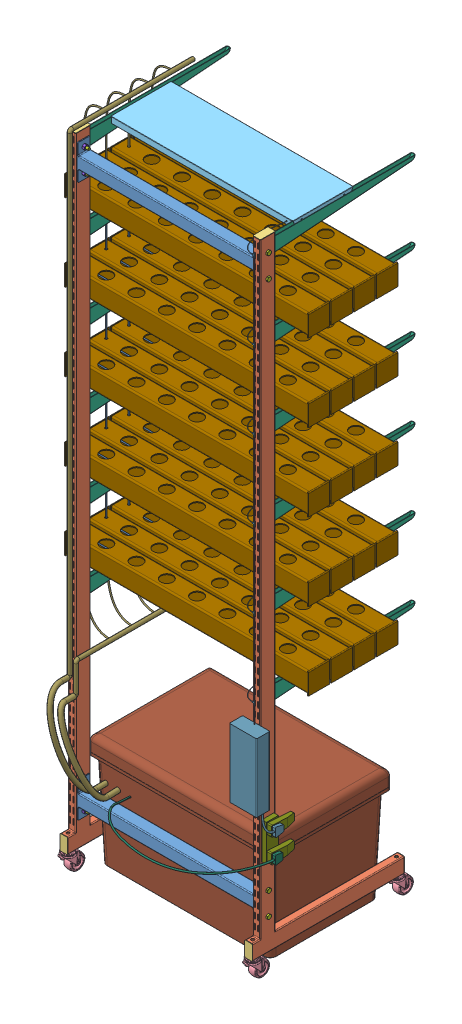
SolidWorks assembly plumbing, configuration Default. Lengths in mm.
Overall size (806 2127.7 608.88).
91 component instances, 17 part files, 242 mates.
Components (placement in the parent):
- TB-600-1: TB-600 [Default] at (0 2029.5 0) size (585 115 40)
- TB-600-2: TB-600 [Default] at (0 205.5 0) size (585 115 40)
- TSU-F-L-P-1: TSU-F-L-P [Default] at (305 113.5 -25) size (25 2050 500)
- TSU-F-L-P-2: TSU-F-L-P [Default] at (-305 113.5 -25) size (25 2050 500)
- TSU-CAP-1: TSU-CAP [Default] at (-305.1 113.6 -39.9) x (-1 0 0) z (0 0 -1) size (25.2 50.2 6.5)
- TSU-CAP-2: TSU-CAP [Default] at (304.9 113.6 -39.9) x (-1 0 0) z (0 0 -1) size (25.2 50.2 6.5)
- TSU-CAP-3: TSU-CAP [Default] at (305.1 1703.4 -25.1) x (1 0 0) z (0 1 0) size (25.2 50.2 6.5)
- TSU-CAP-4: TSU-CAP [Default] at (304.9 113.6 -360.1) size (25.2 50.2 6.5)
- TSU-CAP-5: TSU-CAP [Default] at (-304.9 1703.4 -25.1) x (1 0 0) z (0 1 0) size (25.2 50.2 6.5)
- TSU-CAP-6: TSU-CAP [Default] at (-304.9 113.6 -360.1) size (25.2 50.2 6.5)
- 2834T320_THREADED-STEM SWIVEL CASTER-1: 2834T320_THREADED-STEM SWIVEL CASTER [2834T32] at (305 82.55 -437.5) x (0 0 -1) z (1 0 0) size (67.73 101.87 56.07)
- 2834T320_THREADED-STEM SWIVEL CASTER-2: 2834T320_THREADED-STEM SWIVEL CASTER [2834T32] at (-305 82.55 37.5) x (0 0 -1) z (1 0 0) size (67.73 101.87 56.07)
- 2834T320_THREADED-STEM SWIVEL CASTER-3: 2834T320_THREADED-STEM SWIVEL CASTER [2834T32] at (305 82.55 37.5) x (0 0 -1) z (1 0 0) size (67.73 101.87 56.07)
- 2834T320_THREADED-STEM SWIVEL CASTER-4: 2834T320_THREADED-STEM SWIVEL CASTER [2834T32] at (-305 82.55 -437.5) x (0 0 -1) z (1 0 0) size (67.73 101.87 56.07)
- TSS-600-1: TSS-600 [Default] at (0 818 -198.7822) size (607 37.13 331.17)
- TSUB-1: TSUB [Default] at (305 766.5 -25) x (-1 0 0) z (0 0 -1) size (14.07 50.86 484.03)
- TSUB-2: TSUB [Default] at (-305 766.5 -25) x (-1 0 0) z (0 0 -1) size (14.07 50.86 484.03)
- TSUB-3: TSUB [Default] at (-305 1022.5 -25) x (-1 0 0) z (0 0 -1) size (14.07 50.86 484.03)
- TSUB-4: TSUB [Default] at (305 1022.5 -25) x (-1 0 0) z (0 0 -1) size (14.07 50.86 484.03)
- TSS-600-2: TSS-600 [Default] at (0 1074 -198.7822) size (607 37.13 331.17)
- TSUB-5: TSUB [Default] at (-305 1534.5 -25) x (-1 0 0) z (0 0 -1) size (14.07 50.86 484.03)
- TSUB-6: TSUB [Default] at (305 1534.5 -25) x (-1 0 0) z (0 0 -1) size (14.07 50.86 484.03)
- TSS-600-3: TSS-600 [Default] at (0 1586 -198.7822) size (607 37.13 331.17)
- TSUB-7: TSUB [Default] at (-305 2046.5 -25) x (-1 0 0) z (0 0 -1) size (14.07 50.86 484.03)
- TSUB-8: TSUB [Default] at (305 2046.5 -25) x (-1 0 0) z (0 0 -1) size (14.07 50.86 484.03)
- TSS-600-4: TSS-600 [Default] at (0 2098 -198.7822) size (607 37.13 331.17)
- TSUB-9: TSUB [Default] at (-305 1278.5 -25) x (-1 0 0) z (0 0 -1) size (14.07 50.86 484.03)
- TSUB-10: TSUB [Default] at (305 1278.5 -25) x (-1 0 0) z (0 0 -1) size (14.07 50.86 484.03)
- TSS-600-5: TSS-600 [Default] at (0 1330 -198.7822) size (607 37.13 331.17)
- TSUB-11: TSUB [Default] at (-305 1790.5 -25) x (-1 0 0) z (0 0 -1) size (14.07 50.86 484.03)
- TSUB-12: TSUB [Default] at (305 1790.5 -25) x (-1 0 0) z (0 0 -1) size (14.07 50.86 484.03)
- TSS-600-6: TSS-600 [Default] at (0 1842 -198.7822) size (607 37.13 331.17)
- hex bolt gradeab2_bsi-10: hex bolt gradeab2_bsi [BS EN 28765 - M8x1 x 45 x 22-N] at (322.8 2067 0) x (-1 0 0) z (0 -0.924225 -0.381849) size (50.3 15.01 13)
- hex bolt gradeab2_bsi-11: hex bolt gradeab2_bsi [BS EN 28765 - M8x1 x 45 x 22-N] at (322.8 1992 0) x (-1 0 0) z (0 -0.999974 0.007224) size (50.3 15.01 13)
- hex bolt gradeab2_bsi-12: hex bolt gradeab2_bsi [BS EN 28765 - M8x1 x 45 x 22-N] at (-322.8 2067 0) size (50.3 15.01 13)
- hex bolt gradeab2_bsi-13: hex bolt gradeab2_bsi [BS EN 28765 - M8x1 x 45 x 22-N] at (-322.8 1992 0) size (50.3 15.01 13)
- hex bolt gradeab2_bsi-14: hex bolt gradeab2_bsi [BS EN 28765 - M8x1 x 45 x 22-N] at (-322.8 168 0) size (50.3 15.01 13)
- hex bolt gradeab2_bsi-15: hex bolt gradeab2_bsi [BS EN 28765 - M8x1 x 45 x 22-N] at (-322.8 243 0) size (50.3 15.01 13)
- hex bolt gradeab2_bsi-16: hex bolt gradeab2_bsi [BS EN 28765 - M8x1 x 45 x 22-N] at (322.8 168 0) x (-1 0 0) z (0 0.924225 0.381849) size (50.3 15.01 13)
- hex bolt gradeab2_bsi-17: hex bolt gradeab2_bsi [BS EN 28765 - M8x1 x 45 x 22-N] at (322.8 243 0) x (-1 0 0) z (0 -0.924225 -0.381849) size (50.3 15.01 13)
- hex nut gradec_bsi-1: hex nut gradec_bsi [BS EN 24034 - M8 - N] at (281.6 2067 0) x (0 0 1) z (-1 0 0) size (13 15.01 7.9)
- hex nut gradec_bsi-2: hex nut gradec_bsi [BS EN 24034 - M8 - N] at (281.6 1992 0) x (0 0 1) z (-1 0 0) size (13 15.01 7.9)
- hex nut gradec_bsi-3: hex nut gradec_bsi [BS EN 24034 - M8 - N] at (-281.6 2067 0) x (0 0 -1) z (1 0 0) size (13 15.01 7.9)
- hex nut gradec_bsi-4: hex nut gradec_bsi [BS EN 24034 - M8 - N] at (-281.6 1992 0) x (0 0.383049 0.923728) z (1 0 0) size (13 15.01 7.9)
- hex nut gradec_bsi-5: hex nut gradec_bsi [BS EN 24034 - M8 - N] at (-281.6 243 0) x (0 0 -1) z (1 0 0) size (13 15.01 7.9)
- hex nut gradec_bsi-6: hex nut gradec_bsi [BS EN 24034 - M8 - N] at (281.6 243 0) x (0 0 1) z (-1 0 0) size (13 15.01 7.9)
- hex nut gradec_bsi-7: hex nut gradec_bsi [BS EN 24034 - M8 - N] at (281.6 168 0) x (0 0 1) z (-1 0 0) size (13 15.01 7.9)
- hex nut gradec_bsi-8: hex nut gradec_bsi [BS EN 24034 - M8 - N] at (-281.6 168 0) x (0 0 -1) z (1 0 0) size (13 15.01 7.9)
- GB-600-b-1: GB-600-b [Default] at (0 1106.5 -233.7344) size (806 70 70)
- GB-600-p-1: GB-600-p [Default] at (0 1106.5 -233.7344) size (92 218.31 4)
- GB-600-p-2: GB-600-p [Default] at (0 1106.5 -308.7344) size (92 218.31 4)
- GB-600-b-2: GB-600-b [Default] at (0 1106.5 -308.7344) size (806 70 70)
- GB-600-p-3: GB-600-p [Default] at (0 1106.5 -83.7344) size (92 218.31 4)
- GB-600-b-3: GB-600-b [Default] at (0 1106.5 -83.7344) size (806 70 70)
- GB-600-p-4: GB-600-p [Default] at (0 1106.5 -158.7344) size (92 218.31 4)
- GB-600-b-4: GB-600-b [Default] at (0 1106.5 -158.7344) size (806 70 70)
- GB-600-b-5: GB-600-b [Default] at (0 850.5 -83.7344) size (806 70 70)
- GB-600-b-6: GB-600-b [Default] at (0 850.5 -158.7344) size (806 70 70)
- GB-600-b-7: GB-600-b [Default] at (0 850.5 -233.7344) size (806 70 70)
- GB-600-b-8: GB-600-b [Default] at (0 850.5 -308.7344) size (806 70 70)
- GB-600-b-9: GB-600-b [Default] at (0 1618.5 -83.7344) size (806 70 70)
- GB-600-b-10: GB-600-b [Default] at (0 1618.5 -158.7344) size (806 70 70)
- GB-600-b-11: GB-600-b [Default] at (0 1618.5 -233.7344) size (806 70 70)
- GB-600-b-12: GB-600-b [Default] at (0 1618.5 -308.7344) size (806 70 70)
- GB-600-p-5: GB-600-p [Default] at (0 1618.5 -83.7344) size (92 218.31 4)
- GB-600-p-6: GB-600-p [Default] at (0 1618.5 -158.7344) size (92 218.31 4)
- GB-600-p-7: GB-600-p [Default] at (0 1618.5 -233.7344) size (92 218.31 4)
- GB-600-p-8: GB-600-p [Default] at (0 1618.5 -308.7344) size (92 218.31 4)
- GB-600-p-9: GB-600-p [Default] at (0 1362.5 -308.7344) size (92 218.31 4)
- GB-600-p-10: GB-600-p [Default] at (0 1362.5 -233.7344) size (92 218.31 4)
- GB-600-p-11: GB-600-p [Default] at (0 1362.5 -158.7344) size (92 218.31 4)
- GB-600-p-12: GB-600-p [Default] at (0 1362.5 -83.7344) size (92 218.31 4)
- GB-600-b-13: GB-600-b [Default] at (0 1362.5 -308.7344) size (806 70 70)
- GB-600-b-14: GB-600-b [Default] at (0 1362.5 -233.7344) size (806 70 70)
- GB-600-b-15: GB-600-b [Default] at (0 1362.5 -158.7344) size (806 70 70)
- GB-600-b-16: GB-600-b [Default] at (0 1362.5 -83.7344) size (806 70 70)
- GB-600-p-13: GB-600-p [Default] at (0 1874.5 -308.7344) size (92 218.31 4)
- GB-600-p-14: GB-600-p [Default] at (0 1874.5 -233.7344) size (92 218.31 4)
- GB-600-p-15: GB-600-p [Default] at (0 1874.5 -158.7344) size (92 218.31 4)
- GB-600-p-16: GB-600-p [Default] at (0 1874.5 -83.7344) size (92 218.31 4)
- GB-600-b-17: GB-600-b [Default] at (0 1874.5 -83.7344) size (806 70 70)
- GB-600-b-18: GB-600-b [Default] at (0 1874.5 -158.7344) size (806 70 70)
- GB-600-b-19: GB-600-b [Default] at (0 1874.5 -233.7344) size (806 70 70)
- GB-600-b-20: GB-600-b [Default] at (0 1874.5 -308.7344) size (806 70 70)
- Part3-1: Part3 [Default] at (0 320 -225) size (600 370 400)
- Part4-1: Part4 [Default] at origin
- Part5-1: Part5 [Default] at (-305 113.5 25) size (241.4 2067.5 489.85)
- Part1-1: Part1 [Default] at (0 2060.8692 -198.7822) x (-1 0 0) z (0 -1 0) size (2 2 1357)
- Part2-1: Part2 [Default] at (305 113.5 -25) x (0 0 -1) z (1 0 0) size (82.56 307.09 97.63)
- ele-1: ele [Default] at (0 5 -225) x (1 0 0) z (0 1 0) size (624.24 196.22 364.08)
- power brick-1: power brick [Default] at (317.5 113.5 -25) x (0 0 -1) z (1 0 0) size (82.62 120 30)
Mates (geometry in assembly coordinates):
- Coincident5: coincident aligned: plane of TB-600-2 through (0 205.5 0) normal (1 0 0)
- Coincident6: coincident aligned: plane of TB-600-2 through (0 205.5 0) normal (0 0 1)
- Tangent1: tangent anti-aligned: torus of 2834T320_THREADED-STEM SWIVEL CASTER-1
- Concentric5: concentric anti-aligned: cylinder of TSU-F-L-P-1 through (305 113.5 -437.5) axis (0 -1 0) radius 5.1; cylinder of 2834T320_THREADED-STEM SWIVEL CASTER-1 through (305 101.6 -437.5) axis (0 1 0) radius 4.7625
- Coincident7: coincident anti-aligned: plane of TB-600-2 through (292.5 205.5 0) normal (1 0 0); plane of TSU-F-L-P-1 through (292.5 2113.5 -22) normal (-1 0 0)
- Concentric6: concentric anti-aligned: cylinder of TB-600-2 through (292.5 243 0) axis (-1 0 0) radius 4.5; cylinder of TSU-F-L-P-1 through (290.9 243 0) axis (1 0 0) radius 4.5
- Coincident8: coincident anti-aligned: plane of TSU-F-L-P-1 through (305 63.5 -450) normal (0 -1 0); plane of 2834T320_THREADED-STEM SWIVEL CASTER-1 through (305 63.5 -421.3957) normal (0 1 0)
- Concentric7: concentric anti-aligned: cylinder of TB-600-1 through (292.5 2067 0) axis (-1 0 0) radius 4.5; cylinder of TSU-F-L-P-1 through (292.5 2067 0) axis (1 0 0) radius 4.5
- Coincident9: coincident anti-aligned: plane of TB-600-1 through (292.5 2029.5 0) normal (1 0 0); plane of TSU-F-L-P-1 through (292.5 2113.5 -22) normal (-1 0 0)
- Concentric8: concentric aligned: cylinder of TB-600-2 through (-292.5 168 0) axis (1 0 0) radius 4.5; cylinder of TSU-F-L-P-2 through (-319.1 168 0) axis (1 0 0) radius 4.5
- Coincident10: coincident anti-aligned: plane of TB-600-2 through (-292.5 205.5 0) normal (-1 0 0); plane of TSU-F-L-P-2 through (-292.5 2113.5 -22) normal (1 0 0)
- Concentric9: concentric anti-aligned: cylinder of TSU-F-L-P-2 through (-305 113.5 -437.5) axis (0 -1 0) radius 5.1; cylinder of 2834T320_THREADED-STEM SWIVEL CASTER-4 through (-305 101.6 -437.5) axis (0 1 0) radius 4.7625
- Concentric10: concentric aligned: cylinder of TB-600-1 through (-292.5 1992 0) axis (1 0 0) radius 4.5; cylinder of TSU-F-L-P-2 through (-317.5 1992 0) axis (1 0 0) radius 4.5
- Concentric11: concentric aligned: cylinder of TB-600-1 through (-292.5 2067 0) axis (1 0 0) radius 4.5; cylinder of TSU-F-L-P-2 through (-317.5 2067 0) axis (1 0 0) radius 4.5
- Parallel4: parallel aligned: plane of TSU-F-L-P-1 through (317.5 2113.5 -22) normal (1 0 0); plane of 2834T320_THREADED-STEM SWIVEL CASTER-1 through (316.9062 47.2916 -458.1375) normal (1 0 0)
- Coincident16: coincident anti-aligned: plane of TSU-F-L-P-2 through (-305 63.5 -450) normal (0 -1 0); plane of 2834T320_THREADED-STEM SWIVEL CASTER-4 through (-305 63.5 -421.3957) normal (0 1 0)
- Concentric12: concentric anti-aligned: cylinder of TSU-F-L-P-1 through (305 113.5 37.5) axis (0 -1 0) radius 5.1; cylinder of 2834T320_THREADED-STEM SWIVEL CASTER-3 through (305 101.6 37.5) axis (0 1 0) radius 4.7625
- Coincident17: coincident anti-aligned: plane of TSU-F-L-P-1 through (305 63.5 -450) normal (0 -1 0); plane of 2834T320_THREADED-STEM SWIVEL CASTER-3 through (305 63.5 53.6043) normal (0 1 0)
- Coincident18: coincident aligned: plane of 2834T320_THREADED-STEM SWIVEL CASTER-1 through (316.9062 47.2916 -458.1375) normal (1 0 0); plane of 2834T320_THREADED-STEM SWIVEL CASTER-3 through (316.9062 47.2916 16.8625) normal (1 0 0)
- Concentric13: concentric anti-aligned: cylinder of TSU-F-L-P-2 through (-305 113.5 37.5) axis (0 -1 0) radius 5.1; cylinder of 2834T320_THREADED-STEM SWIVEL CASTER-2 through (-305 101.6 37.5) axis (0 1 0) radius 4.7625
- Coincident19: coincident anti-aligned: plane of TSU-F-L-P-2 through (-305 63.5 -450) normal (0 -1 0); plane of 2834T320_THREADED-STEM SWIVEL CASTER-2 through (-305 63.5 53.6043) normal (0 1 0)
- Parallel6: parallel aligned: plane of TSU-F-L-P-2 through (-317.5 2113.5 -22) normal (-1 0 0); plane of 2834T320_THREADED-STEM SWIVEL CASTER-2 through (-316.9062 47.2916 16.8625) normal (-1 0 0)
- Coincident21: coincident anti-aligned: plane of TSU-F-L-P-1 through (294 2113.5 0) normal (1 0 0); plane of TSU-CAP-4 through (294 113.6 45) normal (-1 0 0)
- Coincident22: coincident anti-aligned: plane of TSU-F-L-P-1 through (314.5 112 -450) normal (0 -1 0); plane of TSU-CAP-4 through (304.9 112 45) normal (0 1 0)
- Coincident23: coincident anti-aligned: plane of TSU-F-L-P-1 through (314.5 110.5 50) normal (0 0 1); plane of TSU-CAP-4 through (304.9 113.6 50) normal (0 0 -1)
- Coincident24: coincident anti-aligned: plane of TSU-F-L-P-2 through (-294 2113.5 0) normal (-1 0 0); plane of TSU-CAP-6 through (-294 113.6 45) normal (1 0 0)
- Coincident25: coincident anti-aligned: plane of TSU-F-L-P-2 through (-295.5 112 -450) normal (0 -1 0); plane of TSU-CAP-6 through (-304.9 112 45) normal (0 1 0)
- Coincident26: coincident anti-aligned: plane of TSU-F-L-P-2 through (-295.5 110.5 50) normal (0 0 1); plane of TSU-CAP-6 through (-304.9 113.6 50) normal (0 0 -1)
- Coincident27: coincident anti-aligned: plane of TSU-F-L-P-1 through (294 2113.5 0) normal (1 0 0); plane of TSU-CAP-2 through (294 113.6 -445) normal (-1 0 0)
- Coincident28: coincident anti-aligned: plane of TSU-F-L-P-1 through (314.5 112 -450) normal (0 -1 0); plane of TSU-CAP-2 through (304.9 112 -445) normal (0 1 0)
- Coincident29: coincident anti-aligned: plane of TSU-F-L-P-1 through (314.5 110.5 -450) normal (0 0 -1); plane of TSU-CAP-2 through (304.9 113.6 -450) normal (0 0 1)
- Coincident30: coincident anti-aligned: plane of TSU-F-L-P-2 through (-316 2113.5 0) normal (1 0 0); plane of TSU-CAP-1 through (-316 113.6 -445) normal (-1 0 0)
- Coincident31: coincident anti-aligned: plane of TSU-F-L-P-2 through (-295.5 112 -450) normal (0 -1 0); plane of TSU-CAP-1 through (-305.1 112 -445) normal (0 1 0)
- Coincident32: coincident anti-aligned: plane of TSU-F-L-P-2 through (-295.5 110.5 -450) normal (0 0 -1); plane of TSU-CAP-1 through (-305.1 113.6 -450) normal (0 0 1)
- Coincident33: coincident anti-aligned: plane of TSU-F-L-P-1 through (316 2113.5 0) normal (-1 0 0); plane of TSU-CAP-3 through (316 2108.5 -25.1) normal (1 0 0)
- Coincident34: coincident anti-aligned: plane of TSU-F-L-P-1 through (314.5 2113.5 -23.5) normal (0 0 1); plane of TSU-CAP-3 through (305.1 2108.5 -23.5) normal (0 0 -1)
- Coincident35: coincident anti-aligned: plane of TSU-F-L-P-1 through (314.5 2113.5 -22) normal (0 1 0); plane of TSU-CAP-3 through (305.1 2113.5 -25.1) normal (0 -1 0)
- Coincident36: coincident anti-aligned: plane of TSU-F-L-P-2 through (-294 2113.5 0) normal (-1 0 0); plane of TSU-CAP-5 through (-294 2108.5 -25.1) normal (1 0 0)
- Coincident37: coincident anti-aligned: plane of TSU-F-L-P-2 through (-295.5 2113.5 -23.5) normal (0 0 1); plane of TSU-CAP-5 through (-304.9 2108.5 -23.5) normal (0 0 -1)
- Coincident38: coincident anti-aligned: plane of TSU-F-L-P-2 through (-295.5 2113.5 -22) normal (0 1 0); plane of TSU-CAP-5 through (-304.9 2113.5 -25.1) normal (0 -1 0)
- Parallel7: parallel aligned: plane of TSU-F-L-P-2 through (-292.5 2113.5 -22) normal (1 0 0); plane of 2834T320_THREADED-STEM SWIVEL CASTER-4 through (-293.0938 47.2916 -458.1375) normal (1 0 0)
- Coincident41: coincident anti-aligned: plane of TSU-F-L-P-1 through (298 273.5 0.001) normal (1 0 0); plane of TSUB-1 through (298 766.5 -25) normal (-1 0 0)
- Coincident42: coincident anti-aligned: plane of TSU-F-L-P-1 through (305 2113.5 -25) normal (0 0 -1); plane of TSUB-1 through (312 766.5 -25) normal (0 0 1)
- Parallel8: parallel: line of TSU-F-L-P-1 through (309 342 -23.5) axis (0 0 -1); plane of TSUB-1 through (298 816.5 -25) normal (0 1 0)
- Coincident44: coincident anti-aligned: plane of TSS-600-1 through (299.5 798 -198.7822) normal (-1 0 0); plane of TSUB-1 through (299.5 766.5 -25) normal (1 0 0)
- Coincident45: coincident anti-aligned: plane of TSS-600-1 through (301 816.5 -100.2822) normal (0 -1 0); plane of TSUB-1 through (298 816.5 -25) normal (0 1 0)
- Coincident46: coincident anti-aligned: plane of TSU-F-L-P-2 through (-312 369.5 0.001) normal (1 0 0); plane of TSUB-2 through (-312 766.5 -25) normal (-1 0 0)
- Coincident47: coincident anti-aligned: plane of TSU-F-L-P-2 through (-305 2113.5 -25) normal (0 0 -1); plane of TSUB-2 through (-312 766.5 -25) normal (0 0 1)
- Coincident48: coincident anti-aligned: plane of TSS-600-1 through (301 816.5 -100.2822) normal (0 -1 0); plane of TSUB-2 through (-312 816.5 -25) normal (0 1 0)
- Coincident49: coincident anti-aligned: plane of TSU-F-L-P-1 through (312 1041.5 0.001) normal (-1 0 0); plane of TSUB-4 through (312 1022.5 -25) normal (1 0 0)
- Coincident50: coincident anti-aligned: plane of TSU-F-L-P-1 through (305 2113.5 -25) normal (0 0 -1); plane of TSUB-4 through (312 1022.5 -25) normal (0 0 1)
- Coincident51: coincident anti-aligned: plane of TSU-F-L-P-2 through (-298 1073.5 0.001) normal (-1 0 0); plane of TSUB-3 through (-298 1022.5 -25) normal (1 0 0)
- Coincident52: coincident anti-aligned: plane of TSU-F-L-P-2 through (-305 2113.5 -25) normal (0 0 -1); plane of TSUB-3 through (-312 1022.5 -25) normal (0 0 1)
- Coincident53: coincident anti-aligned: plane of TSUB-4 through (298 1072.5 -25) normal (0 1 0); plane of TSS-600-2 through (301 1072.5 -100.2822) normal (0 -1 0)
- Coincident54: coincident anti-aligned: plane of TSUB-3 through (-312 1072.5 -25) normal (0 1 0); plane of TSS-600-2 through (301 1072.5 -100.2822) normal (0 -1 0)
- Coincident55: coincident anti-aligned: plane of TSUB-4 through (299.5 1022.5 -25) normal (1 0 0); plane of TSS-600-2 through (299.5 1054 -198.7822) normal (-1 0 0)
- Coincident56: coincident anti-aligned: plane of TSUB-6 through (299.5 1534.5 -25) normal (1 0 0); plane of TSS-600-3 through (299.5 1566 -198.7822) normal (-1 0 0)
- Coincident57: coincident anti-aligned: plane of TSUB-6 through (298 1584.5 -25) normal (0 1 0); plane of TSS-600-3 through (301 1584.5 -100.2822) normal (0 -1 0)
- Coincident58: coincident anti-aligned: plane of TSUB-5 through (-312 1584.5 -25) normal (0 1 0); plane of TSS-600-3 through (301 1584.5 -100.2822) normal (0 -1 0)
- Coincident59: coincident anti-aligned: plane of TSUB-8 through (299.5 2046.5 -25) normal (1 0 0); plane of TSS-600-4 through (299.5 2078 -198.7822) normal (-1 0 0)
- Coincident60: coincident anti-aligned: plane of TSUB-8 through (298 2096.5 -25) normal (0 1 0); plane of TSS-600-4 through (301 2096.5 -100.2822) normal (0 -1 0)
- Coincident61: coincident anti-aligned: plane of TSUB-7 through (-312 2096.5 -25) normal (0 1 0); plane of TSS-600-4 through (301 2096.5 -100.2822) normal (0 -1 0)
- Coincident62: coincident anti-aligned: plane of TSUB-10 through (299.5 1278.5 -25) normal (1 0 0); plane of TSS-600-5 through (299.5 1310 -198.7822) normal (-1 0 0)
- Coincident63: coincident anti-aligned: plane of TSUB-10 through (298 1328.5 -25) normal (0 1 0); plane of TSS-600-5 through (301 1328.5 -100.2822) normal (0 -1 0)
- Coincident64: coincident anti-aligned: plane of TSUB-9 through (-312 1328.5 -25) normal (0 1 0); plane of TSS-600-5 through (301 1328.5 -100.2822) normal (0 -1 0)
- Coincident65: coincident anti-aligned: plane of TSUB-12 through (299.5 1790.5 -25) normal (1 0 0); plane of TSS-600-6 through (299.5 1822 -198.7822) normal (-1 0 0)
- Coincident66: coincident anti-aligned: plane of TSUB-12 through (298 1840.5 -25) normal (0 1 0); plane of TSS-600-6 through (301 1840.5 -100.2822) normal (0 -1 0)
- Coincident67: coincident anti-aligned: plane of TSUB-11 through (-312 1840.5 -25) normal (0 1 0); plane of TSS-600-6 through (301 1840.5 -100.2822) normal (0 -1 0)
- Coincident70: coincident anti-aligned: plane of TSU-F-L-P-1 through (305 2113.5 -25) normal (0 0 -1); plane of TSUB-10 through (298 1278.5 -25) normal (0 0 1)
- Coincident71: coincident anti-aligned: plane of TSU-F-L-P-2 through (-305 2113.5 -25) normal (0 0 -1); plane of TSUB-9 through (-312 1278.5 -25) normal (0 0 1)
- Coincident72: coincident aligned: plane of TSUB-3 through (-298 1022.5 -25) normal (1 0 0); plane of TSUB-9 through (-298 1278.5 -25) normal (1 0 0)
- Coincident73: coincident aligned: plane of TSUB-4 through (298 1022.5 -25) normal (-1 0 0); plane of TSUB-10 through (298 1278.5 -25) normal (-1 0 0)
- Coincident74: coincident anti-aligned: plane of TSU-F-L-P-1 through (305 2113.5 -25) normal (0 0 -1); plane of TSUB-6 through (298 1534.5 -25) normal (0 0 1)
- Coincident75: coincident anti-aligned: plane of TSU-F-L-P-2 through (-305 2113.5 -25) normal (0 0 -1); plane of TSUB-5 through (-312 1534.5 -25) normal (0 0 1)
- Coincident76: coincident aligned: plane of TSUB-5 through (-298 1534.5 -25) normal (1 0 0); plane of TSUB-9 through (-298 1278.5 -25) normal (1 0 0)
- Coincident78: coincident aligned: plane of TSUB-6 through (312 1534.5 -25) normal (1 0 0); plane of TSUB-12 through (312 1790.5 -25) normal (1 0 0)
- Coincident79: coincident aligned: plane of TSUB-6 through (298 1534.5 -25) normal (-1 0 0); plane of TSUB-10 through (298 1278.5 -25) normal (-1 0 0)
- Coincident80: coincident anti-aligned: plane of TSU-F-L-P-1 through (305 2113.5 -25) normal (0 0 -1); plane of TSUB-12 through (298 1790.5 -25) normal (0 0 1)
- Coincident81: coincident anti-aligned: plane of TSU-F-L-P-2 through (-312 1873.5 0.001) normal (1 0 0); plane of TSUB-11 through (-312 1790.5 -25) normal (-1 0 0)
- Coincident82: coincident anti-aligned: plane of TSU-F-L-P-2 through (-305 2113.5 -25) normal (0 0 -1); plane of TSUB-11 through (-312 1790.5 -25) normal (0 0 1)
- Coincident83: coincident anti-aligned: plane of TSU-F-L-P-2 through (-312 1969.5 0.001) normal (1 0 0); plane of TSUB-7 through (-312 2046.5 -25) normal (-1 0 0)
- Coincident84: coincident anti-aligned: plane of TSU-F-L-P-2 through (-305 2113.5 -25) normal (0 0 -1); plane of TSUB-7 through (-312 2046.5 -25) normal (0 0 1)
- Coincident85: coincident anti-aligned: plane of TSU-F-L-P-1 through (298 2001.5 0.001) normal (1 0 0); plane of TSUB-8 through (298 2046.5 -25) normal (-1 0 0)
- Coincident86: coincident anti-aligned: plane of TSU-F-L-P-1 through (305 2113.5 -25) normal (0 0 -1); plane of TSUB-8 through (298 2046.5 -25) normal (0 0 1)
- Coincident89: coincident: line of TSU-F-L-P-1 through (309 2070 -23.5) axis (0 0 -1); plane of TSUB-8 through (333.2603 2070 -25) normal (0 1 0)
- Coincident90: coincident aligned: plane of TSS-600-4 through (301 2098 -298.7822) normal (0 0 -1); plane of TSS-600-6 through (301 1842 -298.7822) normal (0 0 -1)
- Coincident91: coincident aligned: plane of TSS-600-3 through (301 1586 -298.7822) normal (0 0 -1); plane of TSS-600-6 through (301 1842 -298.7822) normal (0 0 -1)
- Coincident93: coincident aligned: plane of TSS-600-3 through (301 1586 -298.7822) normal (0 0 -1); plane of TSS-600-5 through (301 1330 -298.7822) normal (0 0 -1)
- Coincident94: coincident aligned: plane of TSS-600-2 through (301 1074 -298.7822) normal (0 0 -1); plane of TSS-600-5 through (301 1330 -298.7822) normal (0 0 -1)
- Coincident95: coincident aligned: plane of TSS-600-1 through (301 818 -298.7822) normal (0 0 -1); plane of TSS-600-2 through (301 1074 -298.7822) normal (0 0 -1)
- Coincident153: coincident: line of TSU-F-L-P-1 through (312 1814 -23.5) axis (0 0 -1); plane of TSUB-12 through (333.2603 1814 -25) normal (0 1 0)
- Coincident155: coincident: line of TSU-F-L-P-1 through (312 1558 -23.5) axis (0 0 -1); plane of TSUB-6 through (333.2603 1558 -25) normal (0 1 0)
- Coincident157: coincident: line of TSU-F-L-P-1 through (312 1302 -23.5) axis (0 0 -1); plane of TSUB-10 through (333.2603 1302 -25) normal (0 1 0)
- Coincident159: coincident: line of TSU-F-L-P-1 through (312 1046 -23.5) axis (0 0 -1); plane of TSUB-4 through (333.2603 1046 -25) normal (0 1 0)
- Coincident167: coincident: line of TSU-F-L-P-1 through (312 790 -23.5) axis (0 0 -1); plane of TSUB-1 through (333.2603 790 -25) normal (0 1 0)
- Concentric15: concentric aligned: cylinder of TSU-F-L-P-1 through (292.5 2067 0) axis (1 0 0) radius 4.5; cylinder of hex bolt gradeab2_bsi-10 through (322.8 2067 0) axis (1 0 0) radius 4
- Coincident181: coincident anti-aligned: plane of TSU-F-L-P-1 through (317.5 2113.5 -22) normal (1 0 0); plane of hex bolt gradeab2_bsi-10 through (317.5 2069.866 -6.9368) normal (-1 0 0)
- Concentric16: concentric aligned: cylinder of TSU-F-L-P-1 through (292.5 1992 0) axis (1 0 0) radius 4.5; cylinder of hex bolt gradeab2_bsi-11 through (322.8 1992 0) axis (1 0 0) radius 4
- Coincident182: coincident anti-aligned: plane of TSU-F-L-P-1 through (317.5 2113.5 -22) normal (1 0 0); plane of hex bolt gradeab2_bsi-11 through (317.5 1991.9458 -7.5054) normal (-1 0 0)
- Concentric17: concentric anti-aligned: cylinder of TB-600-1 through (-292.5 2067 0) axis (1 0 0) radius 4.5; cylinder of hex bolt gradeab2_bsi-12 through (-322.8 2067 0) axis (-1 0 0) radius 4
- Coincident183: coincident anti-aligned: plane of TSU-F-L-P-2 through (-317.5 2113.5 -22) normal (-1 0 0); plane of hex bolt gradeab2_bsi-12 through (-317.5 2074.5056 0) normal (1 0 0)
- Concentric18: concentric anti-aligned: cylinder of TB-600-1 through (-292.5 1992 0) axis (1 0 0) radius 4.5; cylinder of hex bolt gradeab2_bsi-13 through (-322.8 1992 0) axis (-1 0 0) radius 4
- Coincident184: coincident anti-aligned: plane of TSU-F-L-P-2 through (-317.5 2113.5 -22) normal (-1 0 0); plane of hex bolt gradeab2_bsi-13 through (-317.5 1999.5056 0) normal (1 0 0)
- Concentric19: concentric anti-aligned: cylinder of TB-600-2 through (-292.5 243 0) axis (1 0 0) radius 4.5; cylinder of hex bolt gradeab2_bsi-15 through (-322.8 243 0) axis (-1 0 0) radius 4
- Coincident185: coincident anti-aligned: plane of TSU-F-L-P-2 through (-317.5 2113.5 -22) normal (-1 0 0); plane of hex bolt gradeab2_bsi-15 through (-317.5 250.5056 0) normal (1 0 0)
- Concentric20: concentric anti-aligned: cylinder of TB-600-2 through (-292.5 168 0) axis (1 0 0) radius 4.5; cylinder of hex bolt gradeab2_bsi-14 through (-322.8 168 0) axis (-1 0 0) radius 4
- Coincident186: coincident anti-aligned: plane of TSU-F-L-P-2 through (-317.5 2113.5 -22) normal (-1 0 0); plane of hex bolt gradeab2_bsi-14 through (-317.5 175.5056 0) normal (1 0 0)
- Concentric21: concentric anti-aligned: cylinder of TB-600-2 through (292.5 243 0) axis (-1 0 0) radius 4.5; cylinder of hex bolt gradeab2_bsi-17 through (322.8 243 0) axis (1 0 0) radius 4
- Coincident187: coincident anti-aligned: plane of TSU-F-L-P-1 through (317.5 2113.5 -22) normal (1 0 0); plane of hex bolt gradeab2_bsi-17 through (317.5 245.866 -6.9368) normal (-1 0 0)
- Concentric22: concentric aligned: cylinder of TSU-F-L-P-1 through (290.9 168 0) axis (1 0 0) radius 4.5; cylinder of hex bolt gradeab2_bsi-16 through (322.8 168 0) axis (1 0 0) radius 4
- Coincident188: coincident anti-aligned: plane of TSU-F-L-P-1 through (317.5 2113.5 -22) normal (1 0 0); plane of hex bolt gradeab2_bsi-16 through (317.5 165.134 6.9368) normal (-1 0 0)
- Concentric23: concentric anti-aligned: cylinder of hex bolt gradeab2_bsi-10 through (322.8 2067 0) axis (1 0 0) radius 4; cylinder of hex nut gradec_bsi-1 through (289.5 2067 0) axis (-1 0 0) radius 3.4
- Coincident189: coincident anti-aligned: plane of TB-600-1 through (289.5 2029.5 0) normal (-1 0 0); plane of hex nut gradec_bsi-1 through (289.5 2074.5056 0) normal (1 0 0)
- Concentric24: concentric anti-aligned: cylinder of hex bolt gradeab2_bsi-11 through (322.8 1992 0) axis (1 0 0) radius 4; cylinder of hex nut gradec_bsi-2 through (289.5 1992 0) axis (-1 0 0) radius 3.4
- Coincident190: coincident anti-aligned: plane of TB-600-1 through (289.5 2029.5 0) normal (-1 0 0); plane of hex nut gradec_bsi-2 through (289.5 1999.5056 0) normal (1 0 0)
- Concentric25: concentric anti-aligned: cylinder of hex bolt gradeab2_bsi-12 through (-322.8 2067 0) axis (-1 0 0) radius 4; cylinder of hex nut gradec_bsi-3 through (-289.5 2067 0) axis (1 0 0) radius 3.4
- Coincident191: coincident anti-aligned: plane of TB-600-1 through (-289.5 2029.5 0) normal (1 0 0); plane of hex nut gradec_bsi-3 through (-289.5 2074.5056 0) normal (-1 0 0)
- Concentric26: concentric anti-aligned: cylinder of hex bolt gradeab2_bsi-13 through (-322.8 1992 0) axis (-1 0 0) radius 4; cylinder of hex nut gradec_bsi-4 through (-289.5 1992 0) axis (1 0 0) radius 3.4
- Coincident192: coincident anti-aligned: plane of TB-600-1 through (-289.5 2029.5 0) normal (1 0 0); plane of hex nut gradec_bsi-4 through (-289.5 1985.0669 2.875) normal (-1 0 0)
- Concentric27: concentric anti-aligned: cylinder of hex bolt gradeab2_bsi-15 through (-322.8 243 0) axis (-1 0 0) radius 4; cylinder of hex nut gradec_bsi-5 through (-289.5 243 0) axis (1 0 0) radius 3.4
- Coincident193: coincident anti-aligned: plane of TB-600-2 through (-289.5 205.5 0) normal (1 0 0); plane of hex nut gradec_bsi-5 through (-289.5 250.5056 0) normal (-1 0 0)
- Concentric28: concentric anti-aligned: cylinder of hex bolt gradeab2_bsi-14 through (-322.8 168 0) axis (-1 0 0) radius 4; cylinder of hex nut gradec_bsi-8 through (-289.5 168 0) axis (1 0 0) radius 3.4
- Coincident194: coincident anti-aligned: plane of TB-600-2 through (-289.5 205.5 0) normal (1 0 0); plane of hex nut gradec_bsi-8 through (-289.5 175.5056 0) normal (-1 0 0)
- Concentric29: concentric anti-aligned: cylinder of hex bolt gradeab2_bsi-17 through (322.8 243 0) axis (1 0 0) radius 4; cylinder of hex nut gradec_bsi-6 through (289.5 243 0) axis (-1 0 0) radius 3.4
- Concentric30: concentric anti-aligned: cylinder of hex bolt gradeab2_bsi-16 through (322.8 168 0) axis (1 0 0) radius 4; cylinder of hex nut gradec_bsi-7 through (289.5 168 0) axis (-1 0 0) radius 3.4
- Coincident195: coincident anti-aligned: plane of TB-600-2 through (289.5 205.5 0) normal (-1 0 0); plane of hex nut gradec_bsi-6 through (289.5 250.5056 0) normal (1 0 0)
- Coincident196: coincident anti-aligned: plane of TB-600-2 through (289.5 205.5 0) normal (-1 0 0); plane of hex nut gradec_bsi-7 through (289.5 175.5056 0) normal (1 0 0)
- Concentric31: concentric aligned: cylinder of GB-600-b-1 through (-375 1071.5 -233.7344) axis (0 1 0) radius 2; cylinder of GB-600-p-1 through (-375 877 -233.7344) axis (0 1 0) radius 2
- Distance1: distance = 10 mm aligned: plane of GB-600-p-1 through (-375 1087 -233.7344) normal (0 1 0); plane of GB-600-b-1 through (400 1077 -201.2344) normal (0 1 0)
- Parallel10: parallel anti-aligned: plane of TSU-F-L-P-1 through (305 2113.5 -25) normal (0 0 -1); plane of GB-600-b-1 through (400 1074 -201.2344) normal (0 0 1)
- Coincident201: coincident aligned: plane of GB-600-b-1 through (0 1106.5 -233.7344) normal (1 0 0)
- Coincident202: coincident anti-aligned: plane of TSS-600-2 through (301 1074 -98.7822) normal (0 1 0); plane of GB-600-b-1 through (400 1074 -201.2344) normal (0 -1 0)
- Concentric32: concentric aligned: cylinder of GB-600-p-2 through (-375 877 -308.7344) axis (0 1 0) radius 2; cylinder of GB-600-b-2 through (-375 1071.5 -308.7344) axis (0 1 0) radius 2
- Distance2: distance = 10 mm aligned: plane of GB-600-p-2 through (-375 1087 -308.7344) normal (0 1 0); plane of GB-600-b-2 through (400 1077 -276.2344) normal (0 1 0)
- Concentric33: concentric aligned: cylinder of GB-600-p-3 through (-375 877 -83.7344) axis (0 1 0) radius 2; cylinder of GB-600-b-3 through (-375 1071.5 -83.7344) axis (0 1 0) radius 2
- Distance3: distance = 10 mm aligned: plane of GB-600-p-3 through (-375 1087 -83.7344) normal (0 1 0); plane of GB-600-b-3 through (400 1077 -51.2344) normal (0 1 0)
- Concentric34: concentric aligned: cylinder of GB-600-p-4 through (-375 877 -158.7344) axis (0 1 0) radius 2; cylinder of GB-600-b-4 through (-375 1071.5 -158.7344) axis (0 1 0) radius 2
- Distance4: distance = 10 mm aligned: plane of GB-600-p-4 through (-375 1087 -158.7344) normal (0 1 0); plane of GB-600-b-4 through (400 1077 -126.2344) normal (0 1 0)
- Coincident203: coincident anti-aligned: plane of TSS-600-2 through (301 1074 -98.7822) normal (0 1 0); plane of GB-600-b-2 through (400 1074 -276.2344) normal (0 -1 0)
- Coincident204: coincident anti-aligned: plane of TSS-600-2 through (301 1074 -98.7822) normal (0 1 0); plane of GB-600-b-4 through (400 1074 -126.2344) normal (0 -1 0)
- Coincident205: coincident anti-aligned: plane of TSS-600-2 through (301 1074 -98.7822) normal (0 1 0); plane of GB-600-b-3 through (400 1074 -51.2344) normal (0 -1 0)
- Coincident206: coincident aligned: plane of GB-600-b-1 through (403 1106.5 -233.7344) normal (1 0 0); plane of GB-600-b-4 through (403 1106.5 -158.7344) normal (1 0 0)
- Coincident207: coincident aligned: plane of GB-600-b-3 through (403 1106.5 -83.7344) normal (1 0 0); plane of GB-600-b-4 through (403 1106.5 -158.7344) normal (1 0 0)
- Coincident208: coincident aligned: plane of GB-600-b-1 through (403 1106.5 -233.7344) normal (1 0 0); plane of GB-600-b-2 through (403 1106.5 -308.7344) normal (1 0 0)
- Distance5: distance = 10 mm anti-aligned: plane of GB-600-b-4 through (400 1074 -191.2344) normal (0 0 -1); plane of GB-600-b-1 through (400 1074 -201.2344) normal (0 0 1)
- Distance6: distance = 10 mm anti-aligned: plane of GB-600-b-4 through (400 1074 -126.2344) normal (0 0 1); plane of GB-600-b-3 through (400 1074 -116.2344) normal (0 0 -1)
- Distance7: distance = 10 mm anti-aligned: plane of GB-600-b-1 through (400 1074 -266.2344) normal (0 0 -1); plane of GB-600-b-2 through (400 1074 -276.2344) normal (0 0 1)
- Distance8: distance = 10 mm anti-aligned: plane of GB-600-b-6 through (400 818 -126.2344) normal (0 0 1); plane of GB-600-b-5 through (400 818 -116.2344) normal (0 0 -1)
- Distance9: distance = 10 mm anti-aligned: plane of GB-600-b-6 through (400 818 -191.2344) normal (0 0 -1); plane of GB-600-b-7 through (400 818 -201.2344) normal (0 0 1)
- Coincident212: coincident aligned: plane of GB-600-b-5 through (403 850.5 -83.7344) normal (1 0 0); plane of GB-600-b-6 through (403 850.5 -158.7344) normal (1 0 0)
- Coincident213: coincident aligned: plane of GB-600-b-7 through (403 850.5 -233.7344) normal (1 0 0); plane of GB-600-b-8 through (403 850.5 -308.7344) normal (1 0 0)
- Coincident214: coincident aligned: plane of GB-600-b-6 through (403 850.5 -158.7344) normal (1 0 0); plane of GB-600-b-7 through (403 850.5 -233.7344) normal (1 0 0)
- Distance10: distance = 10 mm anti-aligned: plane of GB-600-b-7 through (400 818 -266.2344) normal (0 0 -1); plane of GB-600-b-8 through (400 818 -276.2344) normal (0 0 1)
- Coincident215: coincident aligned: plane of GB-600-b-7 through (400 818 -201.2344) normal (0 -1 0); plane of GB-600-b-8 through (400 818 -276.2344) normal (0 -1 0)
- Coincident216: coincident aligned: plane of GB-600-b-6 through (400 818 -126.2344) normal (0 -1 0); plane of GB-600-b-7 through (400 818 -201.2344) normal (0 -1 0)
- Coincident217: coincident aligned: plane of GB-600-b-5 through (400 818 -51.2344) normal (0 -1 0); plane of GB-600-b-6 through (400 818 -126.2344) normal (0 -1 0)
- Coincident218: coincident anti-aligned: plane of TSS-600-1 through (301 818 -98.7822) normal (0 1 0); plane of GB-600-b-7 through (400 818 -201.2344) normal (0 -1 0)
- Concentric35: concentric aligned: cylinder of GB-600-p-2 through (-375 877 -308.7344) axis (0 1 0) radius 2; cylinder of GB-600-b-8 through (-375 815.499 -308.7344) axis (0 1 0) radius 4
- Concentric36: concentric aligned: cylinder of GB-600-b-9 through (-375 1583.5 -83.7344) axis (0 1 0) radius 2; cylinder of GB-600-p-5 through (-375 1389 -83.7344) axis (0 1 0) radius 2
- Distance11: distance = 10 mm anti-aligned: plane of GB-600-b-10 through (400 1586 -126.2344) normal (0 0 1); plane of GB-600-b-9 through (400 1586 -116.2344) normal (0 0 -1)
- Concentric37: concentric aligned: cylinder of GB-600-b-12 through (-375 1583.5 -308.7344) axis (0 1 0) radius 2; cylinder of GB-600-p-8 through (-375 1389 -308.7344) axis (0 1 0) radius 2
- Concentric38: concentric aligned: cylinder of GB-600-b-11 through (-375 1583.5 -233.7344) axis (0 1 0) radius 2; cylinder of GB-600-p-7 through (-375 1389 -233.7344) axis (0 1 0) radius 2
- Distance12: distance = 10 mm aligned: plane of GB-600-p-7 through (-375 1599 -233.7344) normal (0 1 0); plane of GB-600-b-11 through (400 1589 -201.2344) normal (0 1 0)
- Distance13: distance = 10 mm anti-aligned: plane of GB-600-b-10 through (400 1586 -191.2344) normal (0 0 -1); plane of GB-600-b-11 through (400 1586 -201.2344) normal (0 0 1)
- Concentric39: concentric aligned: cylinder of GB-600-b-10 through (-375 1583.5 -158.7344) axis (0 1 0) radius 2; cylinder of GB-600-p-6 through (-375 1389 -158.7344) axis (0 1 0) radius 2
- Distance14: distance = 10 mm aligned: plane of GB-600-p-8 through (-375 1599 -308.7344) normal (0 1 0); plane of GB-600-b-12 through (400 1589 -276.2344) normal (0 1 0)
- Distance15: distance = 10 mm aligned: plane of GB-600-p-5 through (-375 1599 -83.7344) normal (0 1 0); plane of GB-600-b-9 through (400 1589 -51.2344) normal (0 1 0)
- Distance16: distance = 10 mm aligned: plane of GB-600-p-6 through (-375 1599 -158.7344) normal (0 1 0); plane of GB-600-b-10 through (400 1589 -126.2344) normal (0 1 0)
- Coincident220: coincident aligned: plane of GB-600-b-9 through (403 1618.5 -83.7344) normal (1 0 0); plane of GB-600-b-10 through (403 1618.5 -158.7344) normal (1 0 0)
- Coincident221: coincident aligned: plane of GB-600-b-11 through (403 1618.5 -233.7344) normal (1 0 0); plane of GB-600-b-12 through (403 1618.5 -308.7344) normal (1 0 0)
- Coincident222: coincident aligned: plane of GB-600-b-10 through (403 1618.5 -158.7344) normal (1 0 0); plane of GB-600-b-11 through (403 1618.5 -233.7344) normal (1 0 0)
- Distance17: distance = 10 mm anti-aligned: plane of GB-600-b-11 through (400 1586 -266.2344) normal (0 0 -1); plane of GB-600-b-12 through (400 1586 -276.2344) normal (0 0 1)
- Coincident223: coincident aligned: plane of GB-600-b-12 through (400 1586 -276.2344) normal (0 -1 0); plane of GB-600-b-9 through (400 1586 -51.2344) normal (0 -1 0)
- Coincident224: coincident aligned: plane of GB-600-b-9 through (400 1586 -51.2344) normal (0 -1 0); plane of GB-600-b-10 through (400 1586 -126.2344) normal (0 -1 0)
- Coincident225: coincident aligned: plane of GB-600-b-10 through (400 1586 -126.2344) normal (0 -1 0); plane of GB-600-b-11 through (400 1586 -201.2344) normal (0 -1 0)
- Coincident226: coincident aligned: plane of GB-600-b-15 through (400 1330 -126.2344) normal (0 -1 0); plane of GB-600-b-16 through (400 1330 -51.2344) normal (0 -1 0)
- Coincident227: coincident aligned: plane of GB-600-b-14 through (400 1330 -201.2344) normal (0 -1 0); plane of GB-600-b-15 through (400 1330 -126.2344) normal (0 -1 0)
- Coincident228: coincident aligned: plane of GB-600-b-14 through (403 1362.5 -233.7344) normal (1 0 0); plane of GB-600-b-15 through (403 1362.5 -158.7344) normal (1 0 0)
- Distance18: distance = 10 mm anti-aligned: plane of GB-600-b-14 through (400 1330 -266.2344) normal (0 0 -1); plane of GB-600-b-13 through (400 1330 -276.2344) normal (0 0 1)
- Coincident229: coincident aligned: plane of GB-600-b-13 through (400 1330 -276.2344) normal (0 -1 0); plane of GB-600-b-16 through (400 1330 -51.2344) normal (0 -1 0)
- Concentric40: concentric aligned: cylinder of GB-600-p-10 through (-375 1133 -233.7344) axis (0 1 0) radius 2; cylinder of GB-600-b-14 through (-375 1327.5 -233.7344) axis (0 1 0) radius 2
- Distance19: distance = 10 mm aligned: plane of GB-600-p-11 through (-375 1343 -158.7344) normal (0 1 0); plane of GB-600-b-15 through (400 1333 -126.2344) normal (0 1 0)
- Concentric41: concentric aligned: cylinder of GB-600-p-12 through (-375 1133 -83.7344) axis (0 1 0) radius 2; cylinder of GB-600-b-16 through (-375 1327.5 -83.7344) axis (0 1 0) radius 2
- Distance20: distance = 10 mm aligned: plane of GB-600-p-12 through (-375 1343 -83.7344) normal (0 1 0); plane of GB-600-b-16 through (400 1333 -51.2344) normal (0 1 0)
- Distance21: distance = 10 mm anti-aligned: plane of GB-600-b-15 through (400 1330 -126.2344) normal (0 0 1); plane of GB-600-b-16 through (400 1330 -116.2344) normal (0 0 -1)
- Coincident230: coincident aligned: plane of GB-600-b-15 through (403 1362.5 -158.7344) normal (1 0 0); plane of GB-600-b-16 through (403 1362.5 -83.7344) normal (1 0 0)
- Distance22: distance = 10 mm anti-aligned: plane of GB-600-b-15 through (400 1330 -191.2344) normal (0 0 -1); plane of GB-600-b-14 through (400 1330 -201.2344) normal (0 0 1)
- Concentric42: concentric aligned: cylinder of GB-600-p-9 through (-375 1133 -308.7344) axis (0 1 0) radius 2; cylinder of GB-600-b-13 through (-375 1327.5 -308.7344) axis (0 1 0) radius 2
- Distance23: distance = 10 mm aligned: plane of GB-600-p-9 through (-375 1343 -308.7344) normal (0 1 0); plane of GB-600-b-13 through (400 1333 -276.2344) normal (0 1 0)
- Distance24: distance = 10 mm aligned: plane of GB-600-p-10 through (-375 1343 -233.7344) normal (0 1 0); plane of GB-600-b-14 through (400 1333 -201.2344) normal (0 1 0)
- Concentric43: concentric aligned: cylinder of GB-600-p-11 through (-375 1133 -158.7344) axis (0 1 0) radius 2; cylinder of GB-600-b-15 through (-375 1327.5 -158.7344) axis (0 1 0) radius 2
- Coincident231: coincident aligned: plane of GB-600-b-13 through (403 1362.5 -308.7344) normal (1 0 0); plane of GB-600-b-14 through (403 1362.5 -233.7344) normal (1 0 0)
- Coincident232: coincident anti-aligned: plane of TSS-600-5 through (301 1330 -98.7822) normal (0 1 0); plane of GB-600-b-13 through (400 1330 -276.2344) normal (0 -1 0)
- Coincident233: coincident aligned: plane of GB-600-b-2 through (400 1074 -341.2344) normal (0 0 -1); plane of GB-600-b-13 through (400 1330 -341.2344) normal (0 0 -1)
- Coincident234: coincident aligned: plane of GB-600-b-2 through (403 1106.5 -308.7344) normal (1 0 0); plane of GB-600-b-13 through (403 1362.5 -308.7344) normal (1 0 0)
- Coincident235: coincident anti-aligned: plane of TSS-600-3 through (301 1586 -98.7822) normal (0 1 0); plane of GB-600-b-12 through (400 1586 -276.2344) normal (0 -1 0)
- Coincident236: coincident aligned: plane of GB-600-b-12 through (-403 1618.5 -308.7344) normal (-1 0 0); plane of GB-600-b-13 through (-403 1362.5 -308.7344) normal (-1 0 0)
- Coincident237: coincident aligned: plane of GB-600-b-12 through (400 1586 -341.2344) normal (0 0 -1); plane of GB-600-b-13 through (400 1330 -341.2344) normal (0 0 -1)
- Coincident238: coincident aligned: plane of GB-600-b-17 through (400 1842 -51.2344) normal (0 -1 0); plane of GB-600-b-18 through (400 1842 -126.2344) normal (0 -1 0)
- Coincident239: coincident aligned: plane of GB-600-b-18 through (400 1842 -126.2344) normal (0 -1 0); plane of GB-600-b-19 through (400 1842 -201.2344) normal (0 -1 0)
- Coincident240: coincident aligned: plane of GB-600-b-18 through (403 1874.5 -158.7344) normal (1 0 0); plane of GB-600-b-19 through (403 1874.5 -233.7344) normal (1 0 0)
- Distance25: distance = 10 mm anti-aligned: plane of GB-600-b-19 through (400 1842 -266.2344) normal (0 0 -1); plane of GB-600-b-20 through (400 1842 -276.2344) normal (0 0 1)
- Coincident241: coincident aligned: plane of GB-600-b-17 through (400 1842 -51.2344) normal (0 -1 0); plane of GB-600-b-20 through (400 1842 -276.2344) normal (0 -1 0)
- Concentric44: concentric aligned: cylinder of GB-600-p-14 through (-375 1645 -233.7344) axis (0 1 0) radius 2; cylinder of GB-600-b-19 through (-375 1839.5 -233.7344) axis (0 1 0) radius 2
- Distance26: distance = 10 mm aligned: plane of GB-600-p-15 through (-375 1855 -158.7344) normal (0 1 0); plane of GB-600-b-18 through (400 1845 -126.2344) normal (0 1 0)
- Concentric45: concentric aligned: cylinder of GB-600-p-16 through (-375 1645 -83.7344) axis (0 1 0) radius 2; cylinder of GB-600-b-17 through (-375 1839.5 -83.7344) axis (0 1 0) radius 2
- Distance27: distance = 10 mm aligned: plane of GB-600-p-16 through (-375 1855 -83.7344) normal (0 1 0); plane of GB-600-b-17 through (400 1845 -51.2344) normal (0 1 0)
- Distance28: distance = 10 mm anti-aligned: plane of GB-600-b-18 through (400 1842 -126.2344) normal (0 0 1); plane of GB-600-b-17 through (400 1842 -116.2344) normal (0 0 -1)
- Coincident242: coincident aligned: plane of GB-600-b-17 through (403 1874.5 -83.7344) normal (1 0 0); plane of GB-600-b-18 through (403 1874.5 -158.7344) normal (1 0 0)
- Distance29: distance = 10 mm anti-aligned: plane of GB-600-b-18 through (400 1842 -191.2344) normal (0 0 -1); plane of GB-600-b-19 through (400 1842 -201.2344) normal (0 0 1)
- Concentric46: concentric aligned: cylinder of GB-600-p-13 through (-375 1645 -308.7344) axis (0 1 0) radius 2; cylinder of GB-600-b-20 through (-375 1839.5 -308.7344) axis (0 1 0) radius 2
- Distance30: distance = 10 mm aligned: plane of GB-600-p-13 through (-375 1855 -308.7344) normal (0 1 0); plane of GB-600-b-20 through (400 1845 -276.2344) normal (0 1 0)
- Distance31: distance = 10 mm aligned: plane of GB-600-p-14 through (-375 1855 -233.7344) normal (0 1 0); plane of GB-600-b-19 through (400 1845 -201.2344) normal (0 1 0)
- Concentric47: concentric aligned: cylinder of GB-600-p-15 through (-375 1645 -158.7344) axis (0 1 0) radius 2; cylinder of GB-600-b-18 through (-375 1839.5 -158.7344) axis (0 1 0) radius 2
- Coincident243: coincident aligned: plane of GB-600-b-19 through (403 1874.5 -233.7344) normal (1 0 0); plane of GB-600-b-20 through (403 1874.5 -308.7344) normal (1 0 0)
- Coincident244: coincident anti-aligned: plane of TSS-600-6 through (301 1842 -98.7822) normal (0 1 0); plane of GB-600-b-20 through (400 1842 -276.2344) normal (0 -1 0)
- Coincident245: coincident aligned: plane of GB-600-b-12 through (400 1586 -341.2344) normal (0 0 -1); plane of GB-600-b-20 through (400 1842 -341.2344) normal (0 0 -1)
- Coincident246: coincident aligned: plane of GB-600-b-12 through (-403 1618.5 -308.7344) normal (-1 0 0); plane of GB-600-b-20 through (-403 1874.5 -308.7344) normal (-1 0 0)
- Coincident247: coincident anti-aligned: plane of Part3-1 through (0 0 -225) normal (0 -1 0)
- Coincident248: coincident aligned: plane of Part3-1 through (0 320 -225) normal (1 0 0)
- Coincident249: coincident anti-aligned: plane of TSU-F-L-P-1 through (305 2113.5 -25) normal (0 0 -1); plane of Part3-1 through (0 370 -25) normal (0 0 1)
- Coincident250: coincident aligned: plane of GB-600-b-2 through (403 1106.5 -308.7344) normal (1 0 0); plane of GB-600-b-8 through (403 850.5 -308.7344) normal (1 0 0)
- InPlace1: in place: plane of TSU-F-L-P-2 through (-305 2113.5 25) normal (0 0 1); plane of ? through (0 0 25) normal (0 0 1); moOrthogonalPlaneRef_w of TSU-F-L-P-2 through (-305 2113.5 25) normal (0 0 1); plane of ? through (0 0 25) normal (0 1 0); plane of TSU-F-L-P-2 through (-305 2113.5 25) normal (0 0 1); plane of ? through (0 0 25) normal (1 0 0); plane of TSU-F-L-P-2 through (-305 2113.5 25) normal (0 0 1); unknown of Part5-1
- Coincident251: coincident aligned: plane of TSU-F-L-P-2; plane of Part5-1
- Coincident252: coincident aligned: moOrthogonalPlaneRef_w of TSU-F-L-P-2 through (-305 113.5 25) normal (0 1 0); plane of Part5-1 through (-305 113.5 25) normal (0 1 0)
- Coincident253: coincident anti-aligned: moOrthogonalPlaneRef_w of TSU-F-L-P-2 through (-305 113.5 25) normal (-1 0 0); plane of Part5-1 through (-305 113.5 25) normal (1 0 0)
- InPlace2: in place: plane of TSS-600-4 through (0 2060.8692 30.3916) normal (0 -1 0); plane of ? through (0 2060.8692 0) normal (0 -1 0); plane of TSS-600-4 through (0 2060.8692 30.3916) normal (0 -1 0); plane of ? through (0 2060.8692 0) normal (0 0 -1); plane of TSS-600-4 through (0 2060.8692 30.3916) normal (0 -1 0); plane of ? through (0 2060.8692 0) normal (-1 0 0); plane of TSS-600-4 through (0 2060.8692 30.3916) normal (0 -1 0); unknown of Part1-1
- Coincident251: coincident aligned: plane of TSS-600-4; plane of Part1-1
- Coincident252: coincident aligned: moOrthogonalPlaneRef_w of TSS-600-4 through (0 2060.8692 -198.7822) normal (0 0 -1); plane of Part1-1 through (0 2060.8692 -198.7822) normal (0 0 -1)
- Coincident253: coincident anti-aligned: moOrthogonalPlaneRef_w of TSS-600-4 through (0 2060.8692 -198.7822) normal (1 0 0); plane of Part1-1 through (0 2060.8692 -198.7822) normal (-1 0 0)
- InPlace3: in place: plane of TSU-F-L-P-1 through (305 113.5 -25) normal (1 0 0); plane of Part2-1 through (305 113.5 -25) normal (1 0 0); plane of TSU-F-L-P-1 through (305 113.5 -25) normal (1 0 0); plane of Part2-1 through (305 113.5 -25) normal (0 1 0); plane of TSU-F-L-P-1 through (305 113.5 -25) normal (1 0 0); plane of Part2-1 through (305 113.5 -25) normal (0 0 -1); plane of TSU-F-L-P-1 through (305 113.5 -25) normal (1 0 0); unknown of Part2-1
- Coincident254: coincident aligned: plane of TSU-F-L-P-1; plane of Part2-1
- Coincident255: coincident aligned: moOrthogonalPlaneRef_w of TSU-F-L-P-1; plane of Part2^Assem1-1 through (305 113.5 -25) normal (0 1 0)
- Coincident256: coincident anti-aligned: moOrthogonalPlaneRef_w of TSU-F-L-P-1 through (-25 0 0) axis (1 0 0); plane of Part2^Assem1-1 through (305 113.5 -25) normal (0 0 -1)
- InPlace4: in place: plane of Part3-1 through (0 5 -225) normal (0 1 0); plane of ? through (0 5 0) normal (0 1 0); plane of Part3-1 through (0 5 -225) normal (0 1 0); plane of ? through (0 5 0) normal (0 0 -1); plane of Part3-1 through (0 5 -225) normal (0 1 0); plane of ? through (0 5 0) normal (1 0 0); plane of Part3-1 through (0 5 -225) normal (0 1 0); unknown of ele-1
- Coincident257: coincident aligned: plane of Part3-1; plane of ele-1
- Coincident258: coincident aligned: moOrthogonalPlaneRef_w of Part3-1 through (0 5 -225) normal (0 0 -1); plane of ele-1 through (0 5 -225) normal (0 0 -1)
- Coincident259: coincident anti-aligned: moOrthogonalPlaneRef_w of Part3-1 through (0 5 -225) normal (-1 0 0); plane of ele-1 through (0 5 -225) normal (1 0 0)
- InPlace5: in place: plane of TSU-F-L-P-1 through (317.5 2113.5 -22) normal (1 0 0); plane of ? through (317.5 0 0) normal (1 0 0); plane of TSU-F-L-P-1 through (317.5 2113.5 -22) normal (1 0 0); plane of ? through (317.5 0 0) normal (0 1 0); plane of TSU-F-L-P-1 through (317.5 2113.5 -22) normal (1 0 0); plane of ? through (317.5 0 0) normal (0 0 -1); plane of TSU-F-L-P-1 through (317.5 2113.5 -22) normal (1 0 0); unknown of power brick-1
- Coincident260: coincident aligned: plane of TSU-F-L-P-1; plane of power brick-1
- Coincident261: coincident aligned: moOrthogonalPlaneRef_w of TSU-F-L-P-1 through (317.5 113.5 -25) normal (0 1 0); plane of Part4^Assem1-1 through (317.5 113.5 -25) normal (0 1 0)
- Coincident262: coincident anti-aligned: moOrthogonalPlaneRef_w of TSU-F-L-P-1 through (317.5 113.5 -25) normal (0 0 1); plane of Part4^Assem1-1 through (317.5 113.5 -25) normal (0 0 -1)
